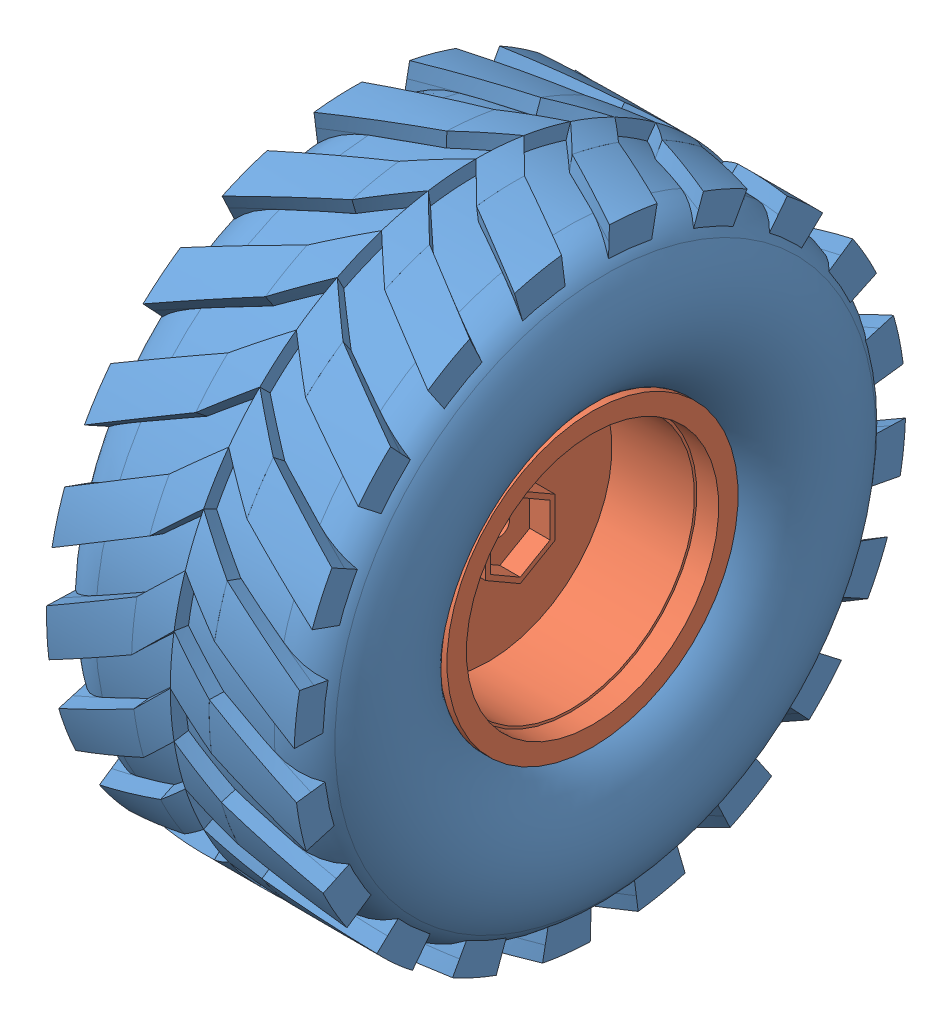
SolidWorks assembly Rueda Izquierda, configuration Predeterminado. Lengths in mm.
Overall size (60 132.17 132.17).
2 component instances, 2 part files, 3 mates.
Components (placement in the parent):
- Pneumatico-1: Pneumatico [Predeterminado] at (-33.0522 7.4496 0) size (60 132.17 132.17)
- Llanta-1: Llanta [Predeterminado] at (-33.0522 7.4496 0) x (-1 0 0) z (0 0 -1) size (48 60 60)
Mates (geometry in assembly coordinates):
- Concéntrica1: concentric: circle of Pneumatico-1; circle of Llanta-1
- Coincidente1: coincident: plane of Pneumatico-1 through (-55.5522 -2.0175 0) normal (-1 0 0); plane of Llanta-1 through (-55.5522 -14.3893 0) normal (1 0 0)
- Coincidente2: coincident anti-aligned: plane of Pneumatico-1 through (-33.0522 7.4496 0) normal (0 0 1); plane of Llanta-1 through (-33.0522 7.4496 0) normal (0 0 -1)
